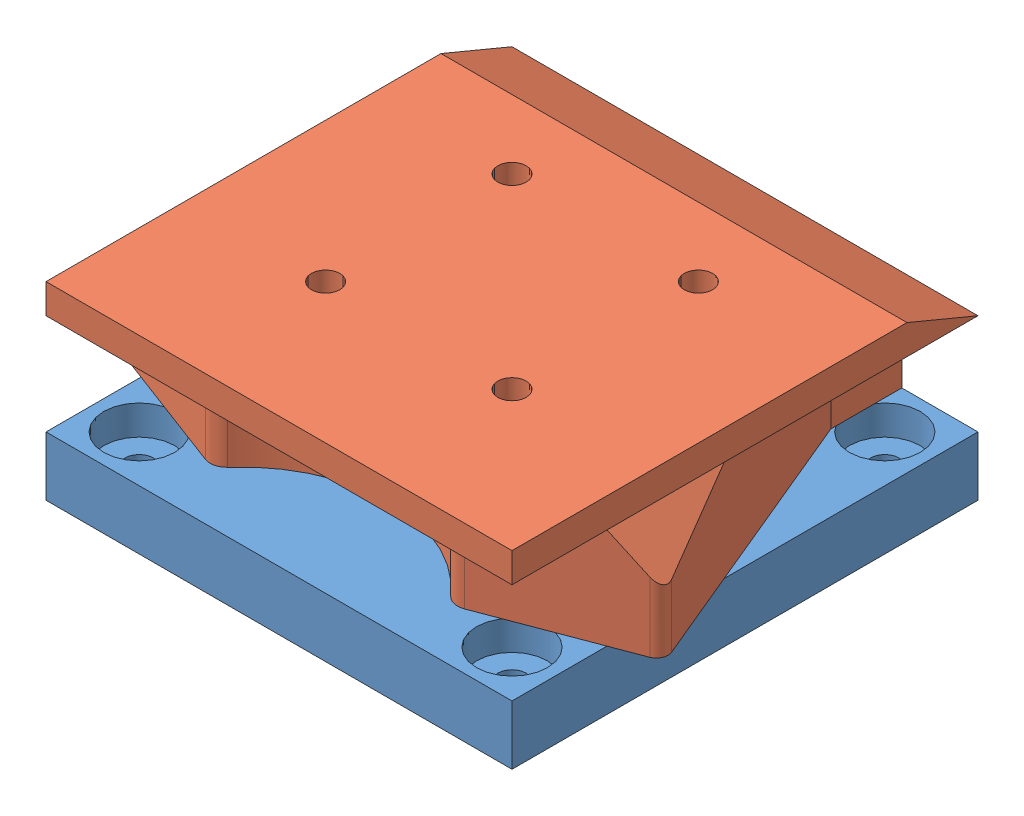
SolidWorks assembly Assem55, configuration Default. Lengths in mm.
Overall size (58.27 20.32 50).
2 component instances, 2 part files, 3 mates.
Components (placement in the parent):
- Lidar base plate-1: Lidar base plate [Default] at (-21.8103 30.5463 59.3733) size (50 6.35 50)
- Lidar inset-1: Lidar inset [Default] at (20.0171 47.6913 9.3734) x (-1 0 0) z (0 0 1) size (58.27 13.97 50)
Mates (geometry in assembly coordinates):
- Coincident1: coincident anti-aligned: plane of Lidar base plate-1 through (-21.8103 36.8963 59.3733) normal (0 1 0); plane of Lidar inset-1 through (31.0953 36.8963 46.7726) normal (0 -1 0)
- Concentric1: concentric aligned: circle of Lidar base plate-1; circle of Lidar inset-1
- Concentric2: concentric aligned: circle of Lidar base plate-1; circle of Lidar inset-1
